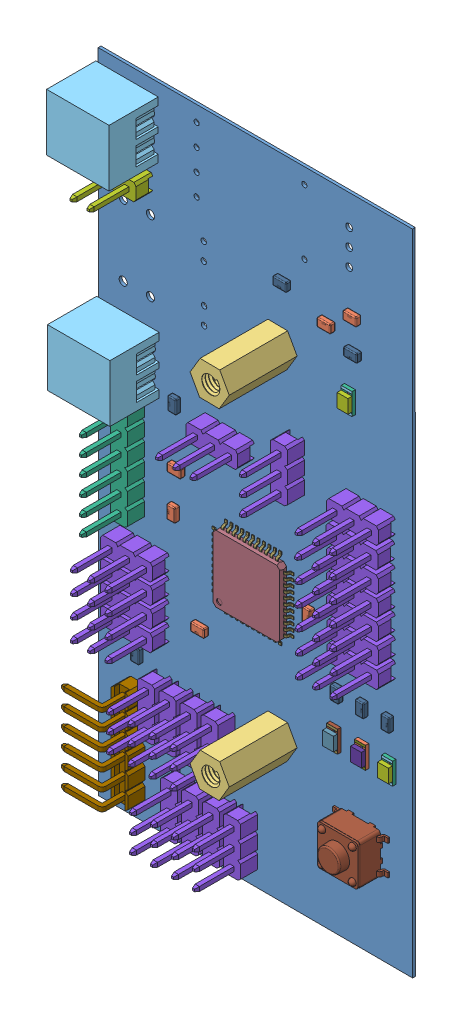
SolidWorks assembly PCBdroneV21, configuration Défaut. Lengths in mm.
Overall size (46.68 95.58 18.25).
198 component instances, 31 part files, 0 mates.
Components (placement in the parent):
- Board-1: Board [Défaut] at (0 0 -0.4115) size (46.33 95.58 0.41)
- C7-1: C7 [Défaut] at origin size (2 1.25 0.78)
  - C0805C-1: C0805C [Défaut] at (32.5373 81.5192 0) x (1 0 0) z (0 -1 0) size (2 0.78 1.25)
- C9-1: C9 [Défaut] at origin size (2 1.25 0.78)
  - C0805C-1: C0805C [Défaut] at (36.3473 84.3132 0) x (1 0 0) z (0 -1 0) size (2 0.78 1.25)
- Cdecoup1-1: Cdecoup1 [Défaut] at origin size (2 1.25 0.78)
  - C0805C-1: C0805C [Défaut] at (13.8939 33.335 0) x (-1 0 0) z (0 1 0) size (2 0.78 1.25)
- Cdecoup2-1: Cdecoup2 [Défaut] at origin size (1.25 2 0.78)
  - C0805C-1: C0805C [Défaut] at (29.9364 43.1801 0) x (0 -1 0) z (-1 0 0) size (2 0.78 1.25)
- Cdecoup4-1: Cdecoup4 [Défaut] at origin size (1.25 2 0.78)
  - C0805C-1: C0805C [Défaut] at (10.0178 46.2787 0) x (0 1 0) z (1 0 0) size (2 0.78 1.25)
- Cde-1: Cde [Défaut] at origin size (2 1.25 0.78)
  - C0805C-1: C0805C [Défaut] at (10.4393 51.9582 0) x (1 0 0) z (0 -1 0) size (2 0.78 1.25)
- D1-1: D1 [Défaut] at origin size (1.6 3.2 1.52)
  - SW3dPS-LED1206G-1: SW3dPS-LED1206G [Défaut] at (35.6997 71.852 0) x (0 1 0) z (0 0 1) size (3.2 1.6 1.52)
    - SW3dPS-LED1206G_Open_CASCADE_STEP_translator_6.2_262.2-1: SW3dPS-LED1206G_Open_CASCADE_STEP_translator_6.2_262.2 [Défaut] at origin size (3.2 1.6 1.1)
      - SW3dPS-LED1206G_352699472-1: SW3dPS-LED1206G_352699472 [Défaut] at (0.6096 0.0254 0.5027) size (0.65 0.76 0.01)
        - SW3dPS-LED1206G_Extruded-1: SW3dPS-LED1206G_Extruded [Défaut] at origin size (0.65 0.76 0.01)
      - SW3dPS-LED1206G_352698192-1: SW3dPS-LED1206G_352698192 [Défaut] at (2.1971 0.0254 0.5027) size (1.14 0.76 0.01)
        - SW3dPS-LED1206G_Extruded4-1: SW3dPS-LED1206G_Extruded4 [Défaut] at origin size (1.14 0.76 0.01)
      - SW3dPS-LED1206G_352697808-1: SW3dPS-LED1206G_352697808 [Défaut] at (0.1016 0.0127 0.5027) size (0.36 1.6 0.01)
        - SW3dPS-LED1206G_Extruded2-1: SW3dPS-LED1206G_Extruded2 [Défaut] at origin size (0.36 1.6 0.01)
      - SW3dPS-LED1206G_352697936-1: SW3dPS-LED1206G_352697936 [Défaut] at (1.524 0.0127 0.0127) size (3.2 1.6 0.49)
        - SW3dPS-LED1206G_Extruded1-1: SW3dPS-LED1206G_Extruded1 [Défaut] at origin size (3.2 1.6 0.49)
      - SW3dPS-LED1206G_352697808-2: SW3dPS-LED1206G_352697808 [Défaut] at (2.9464 0.0127 0.5027) size (0.36 1.6 0.01)
        - SW3dPS-LED1206G_Extruded2-1: SW3dPS-LED1206G_Extruded2 [Défaut] at origin size (0.36 1.6 0.01)
      - SW3dPS-LED1206G_352700880-1: SW3dPS-LED1206G_352700880 [Défaut] at (1.524 0.0127 0.5027) size (2.01 1.6 0.61)
        - SW3dPS-LED1206G_Extruded3-1: SW3dPS-LED1206G_Extruded3 [Défaut] at origin size (2.01 1.6 0.61)
    - SW3dPS-LED1206G_Board-1: SW3dPS-LED1206G_Board [Défaut] at (0 0 -0.4039) size (0.03 0.03 0.42)
- Ddebug1-1: Ddebug1 [Défaut] at origin size (1.6 3.2 1.52)
  - SW3dPS-LED1206R-1: SW3dPS-LED1206R [Défaut] at (33.5406 30.7341 0) x (0 -1 0) z (0 0 1) size (3.2 1.6 1.52)
    - SW3dPS-LED1206R_Board-1: SW3dPS-LED1206R_Board [Défaut] at (0 0 -0.4039) size (0.03 0.03 0.42)
    - SW3dPS-LED1206R_Open_CASCADE_STEP_translator_6.2_278.2-1: SW3dPS-LED1206R_Open_CASCADE_STEP_translator_6.2_278.2 [Défaut] at origin size (3.2 1.6 1.1)
      - SW3dPS-LED1206R_352699472-1: SW3dPS-LED1206R_352699472 [Défaut] at (0.6096 0.0254 0.5027) size (0.65 0.76 0.01)
        - SW3dPS-LED1206R_Extruded3-1: SW3dPS-LED1206R_Extruded3 [Défaut] at origin size (0.65 0.76 0.01)
      - SW3dPS-LED1206R_352697936-1: SW3dPS-LED1206R_352697936 [Défaut] at (1.524 0.0127 0.0127) size (3.2 1.6 0.49)
        - SW3dPS-LED1206R_Extruded1-1: SW3dPS-LED1206R_Extruded1 [Défaut] at origin size (3.2 1.6 0.49)
      - SW3dPS-LED1206R_352697808-1: SW3dPS-LED1206R_352697808 [Défaut] at (2.9464 0.0127 0.5027) size (0.36 1.6 0.01)
        - SW3dPS-LED1206R_Extruded-1: SW3dPS-LED1206R_Extruded [Défaut] at origin size (0.36 1.6 0.01)
      - SW3dPS-LED1206R_352698192-1: SW3dPS-LED1206R_352698192 [Défaut] at (2.1971 0.0254 0.5027) size (1.14 0.76 0.01)
        - SW3dPS-LED1206R_Extruded4-1: SW3dPS-LED1206R_Extruded4 [Défaut] at origin size (1.14 0.76 0.01)
      - SW3dPS-LED1206R_352697808-2: SW3dPS-LED1206R_352697808 [Défaut] at (0.1016 0.0127 0.5027) size (0.36 1.6 0.01)
        - SW3dPS-LED1206R_Extruded-1: SW3dPS-LED1206R_Extruded [Défaut] at origin size (0.36 1.6 0.01)
      - SW3dPS-LED1206R_352701008-1: SW3dPS-LED1206R_352701008 [Défaut] at (1.524 0.0127 0.5027) size (2.01 1.6 0.61)
        - SW3dPS-LED1206R_Extruded2-1: SW3dPS-LED1206R_Extruded2 [Défaut] at origin size (2.01 1.6 0.61)
- Ddebug2-1: Ddebug2 [Défaut] at origin size (1.6 3.2 1.52)
  - SW3dPS-LED1206Y-1: SW3dPS-LED1206Y [Défaut] at (37.6554 30.7341 0) x (0 -1 0) z (0 0 1) size (3.2 1.6 1.52)
    - SW3dPS-LED1206Y_Board-1: SW3dPS-LED1206Y_Board [Défaut] at (0 0 -0.4039) size (0.03 0.03 0.42)
    - SW3dPS-LED1206Y_Open_CASCADE_STEP_translator_6.2_294.2-1: SW3dPS-LED1206Y_Open_CASCADE_STEP_translator_6.2_294.2 [Défaut] at origin size (3.2 1.6 1.1)
      - SW3dPS-LED1206Y_352697808-1: SW3dPS-LED1206Y_352697808 [Défaut] at (0.1016 0.0127 0.5027) size (0.36 1.6 0.01)
        - SW3dPS-LED1206Y_Extruded2-1: SW3dPS-LED1206Y_Extruded2 [Défaut] at origin size (0.36 1.6 0.01)
      - SW3dPS-LED1206Y_352697680-1: SW3dPS-LED1206Y_352697680 [Défaut] at (1.524 0.0127 0.5027) size (2.01 1.6 0.61)
        - SW3dPS-LED1206Y_Extruded4-1: SW3dPS-LED1206Y_Extruded4 [Défaut] at origin size (2.01 1.6 0.61)
      - SW3dPS-LED1206Y_352698192-1: SW3dPS-LED1206Y_352698192 [Défaut] at (2.1971 0.0254 0.5027) size (1.14 0.76 0.01)
        - SW3dPS-LED1206Y_Extruded3-1: SW3dPS-LED1206Y_Extruded3 [Défaut] at origin size (1.14 0.76 0.01)
      - SW3dPS-LED1206Y_352699472-1: SW3dPS-LED1206Y_352699472 [Défaut] at (0.6096 0.0254 0.5027) size (0.65 0.76 0.01)
        - SW3dPS-LED1206Y_Extruded-1: SW3dPS-LED1206Y_Extruded [Défaut] at origin size (0.65 0.76 0.01)
      - SW3dPS-LED1206Y_352697936-1: SW3dPS-LED1206Y_352697936 [Défaut] at (1.524 0.0127 0.0127) size (3.2 1.6 0.49)
        - SW3dPS-LED1206Y_Extruded1-1: SW3dPS-LED1206Y_Extruded1 [Défaut] at origin size (3.2 1.6 0.49)
      - SW3dPS-LED1206Y_352697808-2: SW3dPS-LED1206Y_352697808 [Défaut] at (2.9464 0.0127 0.5027) size (0.36 1.6 0.01)
        - SW3dPS-LED1206Y_Extruded2-1: SW3dPS-LED1206Y_Extruded2 [Défaut] at origin size (0.36 1.6 0.01)
- Ddebug3-1: Ddebug3 [Défaut] at origin size (1.6 3.2 1.52)
  - SW3dPS-LED1206G-1: SW3dPS-LED1206G [Défaut] at (41.6433 30.7086 0) x (0 -1 0) z (0 0 1) size (3.2 1.6 1.52)
    - SW3dPS-LED1206G_Open_CASCADE_STEP_translator_6.2_262.2-1: SW3dPS-LED1206G_Open_CASCADE_STEP_translator_6.2_262.2 [Défaut] at origin size (3.2 1.6 1.1)
      - SW3dPS-LED1206G_352699472-1: SW3dPS-LED1206G_352699472 [Défaut] at (0.6096 0.0254 0.5027) size (0.65 0.76 0.01)
        - SW3dPS-LED1206G_Extruded-1: SW3dPS-LED1206G_Extruded [Défaut] at origin size (0.65 0.76 0.01)
      - SW3dPS-LED1206G_352698192-1: SW3dPS-LED1206G_352698192 [Défaut] at (2.1971 0.0254 0.5027) size (1.14 0.76 0.01)
        - SW3dPS-LED1206G_Extruded4-1: SW3dPS-LED1206G_Extruded4 [Défaut] at origin size (1.14 0.76 0.01)
      - SW3dPS-LED1206G_352697808-1: SW3dPS-LED1206G_352697808 [Défaut] at (0.1016 0.0127 0.5027) size (0.36 1.6 0.01)
        - SW3dPS-LED1206G_Extruded2-1: SW3dPS-LED1206G_Extruded2 [Défaut] at origin size (0.36 1.6 0.01)
      - SW3dPS-LED1206G_352697936-1: SW3dPS-LED1206G_352697936 [Défaut] at (1.524 0.0127 0.0127) size (3.2 1.6 0.49)
        - SW3dPS-LED1206G_Extruded1-1: SW3dPS-LED1206G_Extruded1 [Défaut] at origin size (3.2 1.6 0.49)
      - SW3dPS-LED1206G_352697808-2: SW3dPS-LED1206G_352697808 [Défaut] at (2.9464 0.0127 0.5027) size (0.36 1.6 0.01)
        - SW3dPS-LED1206G_Extruded2-1: SW3dPS-LED1206G_Extruded2 [Défaut] at origin size (0.36 1.6 0.01)
      - SW3dPS-LED1206G_352700880-1: SW3dPS-LED1206G_352700880 [Défaut] at (1.524 0.0127 0.5027) size (2.01 1.6 0.61)
        - SW3dPS-LED1206G_Extruded3-1: SW3dPS-LED1206G_Extruded3 [Défaut] at origin size (2.01 1.6 0.61)
    - SW3dPS-LED1206G_Board-1: SW3dPS-LED1206G_Board [Défaut] at (0 0 -0.4039) size (0.03 0.03 0.42)
- HOLE1-1: HOLE1 [Défaut] at origin size (5.77 5.05 18.25)
  - User_Library-Spacer-M3-10mm-1: User_Library-Spacer-M3-10mm [Défaut] at (25.0001 75.0001 0) x (1 0 0) z (0 -1 0) size (5.77 18.25 5.05)
  - User_Library-Female_screw_M3-1: User_Library-Female_screw_M3 [Défaut] at (25.0001 75.0001 -3.8) x (1 0 0) z (0 -1 0) size (5.77 3 5.05)
- HOLE2-1: HOLE2 [Défaut] at origin size (5.77 5.05 18.25)
  - User_Library-Spacer-M3-10mm-1: User_Library-Spacer-M3-10mm [Défaut] at (25.0001 25.0001 0) x (1 0 0) z (0 -1 0) size (5.77 18.25 5.05)
  - User_Library-Female_screw_M3-1: User_Library-Female_screw_M3 [Défaut] at (25.0001 25.0001 -3.8) x (1 0 0) z (0 -1 0) size (5.77 3 5.05)
- PBat-1: PBat [Défaut] at origin size (9.2 8.4 10.65)
  - User_Library-CTB93HD_2-1: User_Library-CTB93HD_2 [Défaut] at (6.2231 95.347 0) x (0 0 -1) z (0 1 0) size (10.65 9.2 8.4)
- Paccelgyro-1: Paccelgyro [Défaut] at origin size (2.5 15.24 11.2)
  - pin_header_aw140-eg-g06d-1: pin_header_aw140-eg-g06d [Défaut] at (4.1657 50.6475 0) x (0 -1 0) z (1 0 0) size (15.24 11.2 2.5)
- Palarm-1: Palarm [Défaut] at origin size (5.08 2.5 11.2)
  - pin_header_aw140-eg-g02d-1: pin_header_aw140-eg-g02d [Défaut] at (4.0387 86.3855 0) x (1 0 0) z (0 1 0) size (5.08 11.2 2.5)
- PAN0-1: PAN0 [Défaut] at origin size (2.5 7.62 11.2)
  - pin_header_aw140-eg-g03d-1: pin_header_aw140-eg-g03d [Défaut] at (8.1789 21.0819 0) x (0 -1 0) z (1 0 0) size (7.62 11.2 2.5)
- PAN1-1: PAN1 [Défaut] at origin size (2.5 7.62 11.2)
  - pin_header_aw140-eg-g03d-1: pin_header_aw140-eg-g03d [Défaut] at (11.3031 21.0819 0) x (0 -1 0) z (1 0 0) size (7.62 11.2 2.5)
- PAN6-1: PAN6 [Défaut] at origin size (2.5 7.62 11.2)
  - pin_header_aw140-eg-g03d-1: pin_header_aw140-eg-g03d [Défaut] at (14.4019 21.0819 0) x (0 -1 0) z (1 0 0) size (7.62 11.2 2.5)
- PAN7-1: PAN7 [Défaut] at origin size (2.5 7.62 11.2)
  - pin_header_aw140-eg-g03d-1: pin_header_aw140-eg-g03d [Défaut] at (17.5007 21.1073 0) x (0 -1 0) z (1 0 0) size (7.62 11.2 2.5)
- Pext-1: Pext [Défaut] at origin size (9.2 8.4 10.65)
  - User_Library-CTB93HD_2-1: User_Library-CTB93HD_2 [Défaut] at (6.3501 65.375 0) x (0 0 -1) z (0 1 0) size (10.65 9.2 8.4)
- Pickit-1: Pickit [Défaut] at origin size (7.1 15.04 11.14)
  - pin_header_aw140-ea-g06h-1: pin_header_aw140-ea-g06h [Défaut] at (4.2419 14.3255 2.5) x (0 1 0) z (1 0 0) size (15.04 11.14 7.1)
- Pjump0-1: Pjump0 [Défaut] at origin size (2.5 7.62 11.2)
  - pin_header_aw140-eg-g03d-1: pin_header_aw140-eg-g03d [Défaut] at (11.5569 9.9315 0) x (0 1 0) z (-1 0 0) size (7.62 11.2 2.5)
- Pjump1-1: Pjump1 [Défaut] at origin size (2.5 7.62 11.2)
  - pin_header_aw140-eg-g03d-1: pin_header_aw140-eg-g03d [Défaut] at (14.6473 9.9315 0) x (0 1 0) z (-1 0 0) size (7.62 11.2 2.5)
- Pjump6-1: Pjump6 [Défaut] at origin size (2.5 7.62 11.2)
  - pin_header_aw140-eg-g03d-1: pin_header_aw140-eg-g03d [Défaut] at (17.7376 9.9315 0) x (0 1 0) z (-1 0 0) size (7.62 11.2 2.5)
- Pjump7-1: Pjump7 [Défaut] at origin size (2.5 7.62 11.2)
  - pin_header_aw140-eg-g03d-1: pin_header_aw140-eg-g03d [Défaut] at (20.8279 9.9315 0) x (0 1 0) z (-1 0 0) size (7.62 11.2 2.5)
- Prec-1: Prec [Défaut] at origin size (7.62 2.5 11.2)
  - pin_header_aw140-eg-g03d-1: pin_header_aw140-eg-g03d [Défaut] at (38.5065 60.4013 0) x (1 0 0) z (0 1 0) size (7.62 11.2 2.5)
- Prec2-1: Prec2 [Défaut] at origin size (7.62 2.5 11.2)
  - pin_header_aw140-eg-g03d-1: pin_header_aw140-eg-g03d [Défaut] at (38.4811 51.1303 0) x (1 0 0) z (0 1 0) size (7.62 11.2 2.5)
- Prec3-1: Prec3 [Défaut] at origin size (7.62 2.5 11.2)
  - pin_header_aw140-eg-g03d-1: pin_header_aw140-eg-g03d [Défaut] at (38.4811 54.1529 0) x (1 0 0) z (0 1 0) size (7.62 11.2 2.5)
- Prec4-1: Prec4 [Défaut] at origin size (7.62 2.5 11.2)
  - pin_header_aw140-eg-g03d-1: pin_header_aw140-eg-g03d [Défaut] at (38.4303 57.2263 0) x (1 0 0) z (0 1 0) size (7.62 11.2 2.5)
- Prec5-1: Prec5 [Défaut] at origin size (7.62 2.5 11.2)
  - pin_header_aw140-eg-g03d-1: pin_header_aw140-eg-g03d [Défaut] at (38.5319 42.0117 0) x (1 0 0) z (0 1 0) size (7.62 11.2 2.5)
- Prec6-1: Prec6 [Défaut] at origin size (7.62 2.5 11.2)
  - pin_header_aw140-eg-g03d-1: pin_header_aw140-eg-g03d [Défaut] at (38.5319 45.0597 0) x (1 0 0) z (0 1 0) size (7.62 11.2 2.5)
- Prec7-1: Prec7 [Défaut] at origin size (7.62 2.5 11.2)
  - pin_header_aw140-eg-g03d-1: pin_header_aw140-eg-g03d [Défaut] at (38.5065 48.1331 0) x (1 0 0) z (0 1 0) size (7.62 11.2 2.5)
- Psend1-1: Psend1 [Défaut] at origin size (7.62 2.5 11.2)
  - pin_header_aw140-eg-g03d-1: pin_header_aw140-eg-g03d [Défaut] at (5.3847 39.0651 0) x (-1 0 0) z (0 -1 0) size (7.62 11.2 2.5)
- Psend2-1: Psend2 [Défaut] at origin size (7.62 2.5 11.2)
  - pin_header_aw140-eg-g03d-1: pin_header_aw140-eg-g03d [Défaut] at (5.3847 36.0595 0) x (-1 0 0) z (0 -1 0) size (7.62 11.2 2.5)
- Psend3-1: Psend3 [Défaut] at origin size (7.62 2.5 11.2)
  - pin_header_aw140-eg-g03d-1: pin_header_aw140-eg-g03d [Défaut] at (5.3847 33.0538 0) x (-1 0 0) z (0 -1 0) size (7.62 11.2 2.5)
- Psend4-1: Psend4 [Défaut] at origin size (7.62 2.5 11.2)
  - pin_header_aw140-eg-g03d-1: pin_header_aw140-eg-g03d [Défaut] at (5.3847 30.0481 0) x (-1 0 0) z (0 -1 0) size (7.62 11.2 2.5)
- Pservo-1: Pservo [Défaut] at origin size (2.5 7.62 11.2)
  - pin_header_aw140-eg-g03d-1: pin_header_aw140-eg-g03d [Défaut] at (27.7367 61.1633 0) x (0 1 0) z (-1 0 0) size (7.62 11.2 2.5)
- Puart-1: Puart [Défaut] at origin size (7.62 2.5 11.2)
  - pin_header_aw140-eg-g03d-1: pin_header_aw140-eg-g03d [Défaut] at (17.9323 59.7153 0) x (-1 0 0) z (0 -1 0) size (7.62 11.2 2.5)
- R1-1: R1 [Défaut] at origin size (2 1.25 0.78)
  - SW3dPS-0805_SMD_Resistor-1: SW3dPS-0805_SMD_Resistor [Défaut] at (36.449 79.7259 0) x (-1 0 0) z (0 1 0) size (2 0.78 1.25)
- Rd1-1: Rd1 [Défaut] at origin size (1.25 2 0.78)
  - SW3dPS-0805_SMD_Resistor-1: SW3dPS-0805_SMD_Resistor [Défaut] at (34.0869 35.2298 0) x (0 -1 0) z (-1 0 0) size (2 0.78 1.25)
- Rd2-1: Rd2 [Défaut] at origin size (1.25 2 0.78)
  - SW3dPS-0805_SMD_Resistor-1: SW3dPS-0805_SMD_Resistor [Défaut] at (37.7953 35.2044 0) x (0 -1 0) z (-1 0 0) size (2 0.78 1.25)
- Rd3-1: Rd3 [Défaut] at origin size (1.25 2 0.78)
  - SW3dPS-0805_SMD_Resistor-1: SW3dPS-0805_SMD_Resistor [Défaut] at (41.5799 35.2298 0) x (0 -1 0) z (-1 0 0) size (2 0.78 1.25)
- reset-1: reset [Défaut] at origin size (8.15 6 5.05)
  - CircuitWorks-TACT_SMD_6X6-1: CircuitWorks-TACT_SMD_6X6 [Défaut] at (37.4613 17.8159 0) x (1 0 0) z (0 -1 0) size (8.15 5.05 6)
- Rp1-1: Rp1 [Défaut] at origin size (1.25 2 0.78)
  - SW3dPS-0805_SMD_Resistor-1: SW3dPS-0805_SMD_Resistor [Défaut] at (4.6735 25.527 0) x (0 1 0) z (1 0 0) size (2 0.78 1.25)
- Rpup-1: Rpup [Défaut] at origin size (1.25 2 0.78)
  - SW3dPS-0805_SMD_Resistor-1: SW3dPS-0805_SMD_Resistor [Défaut] at (10.1599 60.168 0) x (0 1 0) z (1 0 0) size (2 0.78 1.25)
- Rset-1: Rset [Défaut] at origin size (2 1.25 0.78)
  - SW3dPS-0805_SMD_Resistor-1: SW3dPS-0805_SMD_Resistor [Défaut] at (26.035 83.5659 0) x (-1 0 0) z (0 1 0) size (2 0.78 1.25)
- U1-1: U1 [Défaut] at origin size (12 12 1.06)
  - User_Library-TQFP-44-1: User_Library-TQFP-44 [Défaut] at (21.4631 42.8961 0.55) size (12 12 1.06)
    - User_Library-TQFP-44_pins_TQFP_pin_TQFP_035_1-1: User_Library-TQFP-44_pins_TQFP_pin_TQFP_035_1 [Défaut] at (6 2.225 -0.5) x (0 1 0) z (1 0 0) size (0.35 0.62 1)
    - User_Library-TQFP-44_pins_TQFP_pin_TQFP_035_1-2: User_Library-TQFP-44_pins_TQFP_pin_TQFP_035_1 [Défaut] at (-6 -2.225 -0.5) x (0 -1 0) z (-1 0 0) size (0.35 0.62 1)
    - User_Library-TQFP-44_pins_TQFP_pin_TQFP_035_1-3: User_Library-TQFP-44_pins_TQFP_pin_TQFP_035_1 [Défaut] at (-6 3.375 -0.5) x (0 -1 0) z (-1 0 0) size (0.35 0.62 1)
    - User_Library-TQFP-44_pins_TQFP_pin_TQFP_035_1-4: User_Library-TQFP-44_pins_TQFP_pin_TQFP_035_1 [Défaut] at (6 -0.975 -0.5) x (0 1 0) z (1 0 0) size (0.35 0.62 1)
    - User_Library-TQFP-44_pins_TQFP_pin_TQFP_035_1-5: User_Library-TQFP-44_pins_TQFP_pin_TQFP_035_1 [Défaut] at (3.375 6 -0.5) x (-1 0 0) z (0 1 0) size (0.35 0.62 1)
    - User_Library-TQFP-44_pins_TQFP_pin_TQFP_035_1-6: User_Library-TQFP-44_pins_TQFP_pin_TQFP_035_1 [Défaut] at (-6 0.975 -0.5) x (0 -1 0) z (-1 0 0) size (0.35 0.62 1)
    - User_Library-TQFP-44_pins_TQFP_pin_TQFP_035_1-7: User_Library-TQFP-44_pins_TQFP_pin_TQFP_035_1 [Défaut] at (0.625 -6 -0.5) x (1 0 0) z (0 -1 0) size (0.35 0.62 1)
    - User_Library-TQFP-44_pins_TQFP_pin_TQFP_035_1-8: User_Library-TQFP-44_pins_TQFP_pin_TQFP_035_1 [Défaut] at (0.175 6 -0.5) x (-1 0 0) z (0 1 0) size (0.35 0.62 1)
    - User_Library-TQFP-44_pins_TQFP_pin_TQFP_035_1-9: User_Library-TQFP-44_pins_TQFP_pin_TQFP_035_1 [Défaut] at (-2.575 -6 -0.5) x (1 0 0) z (0 -1 0) size (0.35 0.62 1)
    - User_Library-TQFP-44_pins_TQFP_pin_TQFP_035_1-10: User_Library-TQFP-44_pins_TQFP_pin_TQFP_035_1 [Défaut] at (-3.375 -6 -0.5) x (1 0 0) z (0 -1 0) size (0.35 0.62 1)
    - User_Library-TQFP-44_pins_TQFP_pin_TQFP_035_1-11: User_Library-TQFP-44_pins_TQFP_pin_TQFP_035_1 [Défaut] at (6 1.425 -0.5) x (0 1 0) z (1 0 0) size (0.35 0.62 1)
    - User_Library-TQFP-44_pins_TQFP_pin_TQFP_035_1-12: User_Library-TQFP-44_pins_TQFP_pin_TQFP_035_1 [Défaut] at (-6 -3.025 -0.5) x (0 -1 0) z (-1 0 0) size (0.35 0.62 1)
    - User_Library-TQFP-44_pins_TQFP_pin_TQFP_035_1-13: User_Library-TQFP-44_pins_TQFP_pin_TQFP_035_1 [Défaut] at (2.575 6 -0.5) x (-1 0 0) z (0 1 0) size (0.35 0.62 1)
    - User_Library-TQFP-44_pins_TQFP_pin_TQFP_035_1-14: User_Library-TQFP-44_pins_TQFP_pin_TQFP_035_1 [Défaut] at (1.775 6 -0.5) x (-1 0 0) z (0 1 0) size (0.35 0.62 1)
    - User_Library-TQFP-44_pins_TQFP_pin_TQFP_035_1-15: User_Library-TQFP-44_pins_TQFP_pin_TQFP_035_1 [Défaut] at (-0.975 -6 -0.5) x (1 0 0) z (0 -1 0) size (0.35 0.62 1)
    - User_Library-TQFP-44_pins_TQFP_pin_TQFP_035_1-16: User_Library-TQFP-44_pins_TQFP_pin_TQFP_035_1 [Défaut] at (-0.175 -6 -0.5) x (1 0 0) z (0 -1 0) size (0.35 0.62 1)
    - User_Library-TQFP-44_pins_TQFP_pin_TQFP_035_1-17: User_Library-TQFP-44_pins_TQFP_pin_TQFP_035_1 [Défaut] at (-0.625 6 -0.5) x (-1 0 0) z (0 1 0) size (0.35 0.62 1)
    - User_Library-TQFP-44_pins_TQFP_pin_TQFP_035_1-18: User_Library-TQFP-44_pins_TQFP_pin_TQFP_035_1 [Défaut] at (-3.025 6 -0.5) x (-1 0 0) z (0 1 0) size (0.35 0.62 1)
    - User_Library-TQFP-44_pins_TQFP_pin_TQFP_035_1-19: User_Library-TQFP-44_pins_TQFP_pin_TQFP_035_1 [Défaut] at (6 -4.175 -0.5) x (0 1 0) z (1 0 0) size (0.35 0.62 1)
    - User_Library-TQFP-44_pins_TQFP_pin_TQFP_035_1-20: User_Library-TQFP-44_pins_TQFP_pin_TQFP_035_1 [Défaut] at (6 3.025 -0.5) x (0 1 0) z (1 0 0) size (0.35 0.62 1)
    - User_Library-TQFP-44_pins_TQFP_pin_TQFP_035_1-21: User_Library-TQFP-44_pins_TQFP_pin_TQFP_035_1 [Défaut] at (2.225 -6 -0.5) x (1 0 0) z (0 -1 0) size (0.35 0.62 1)
    - User_Library-TQFP-44_pins_TQFP_pin_TQFP_035_1-22: User_Library-TQFP-44_pins_TQFP_pin_TQFP_035_1 [Défaut] at (-6 -1.425 -0.5) x (0 -1 0) z (-1 0 0) size (0.35 0.62 1)
    - User_Library-TQFP-44_pins_TQFP_pin_TQFP_035_1-23: User_Library-TQFP-44_pins_TQFP_pin_TQFP_035_1 [Défaut] at (-6 4.175 -0.5) x (0 -1 0) z (-1 0 0) size (0.35 0.62 1)
    - User_Library-TQFP-44_pins_TQFP_pin_TQFP_035_1-24: User_Library-TQFP-44_pins_TQFP_pin_TQFP_035_1 [Défaut] at (6 -0.175 -0.5) x (0 1 0) z (1 0 0) size (0.35 0.62 1)
    - User_Library-TQFP-44_pins_TQFP_pin_TQFP_035_1-25: User_Library-TQFP-44_pins_TQFP_pin_TQFP_035_1 [Défaut] at (4.175 6 -0.5) x (-1 0 0) z (0 1 0) size (0.35 0.62 1)
    - User_Library-TQFP-44_pins_TQFP_pin_TQFP_035_1-26: User_Library-TQFP-44_pins_TQFP_pin_TQFP_035_1 [Défaut] at (-6 1.775 -0.5) x (0 -1 0) z (-1 0 0) size (0.35 0.62 1)
    - User_Library-TQFP-44_pins_TQFP_pin_TQFP_035_1-27: User_Library-TQFP-44_pins_TQFP_pin_TQFP_035_1 [Défaut] at (-6 0.175 -0.5) x (0 -1 0) z (-1 0 0) size (0.35 0.62 1)
    - User_Library-TQFP-44_pins_TQFP_pin_TQFP_035_1-28: User_Library-TQFP-44_pins_TQFP_pin_TQFP_035_1 [Défaut] at (6 -1.775 -0.5) x (0 1 0) z (1 0 0) size (0.35 0.62 1)
    - User_Library-TQFP-44_pins_TQFP_pin_TQFP_035_1-29: User_Library-TQFP-44_pins_TQFP_pin_TQFP_035_1 [Défaut] at (-3.825 6 -0.5) x (-1 0 0) z (0 1 0) size (0.35 0.62 1)
    - User_Library-TQFP-44_pins_TQFP_pin_TQFP_035_1-30: User_Library-TQFP-44_pins_TQFP_pin_TQFP_035_1 [Défaut] at (6 0.625 -0.5) x (0 1 0) z (1 0 0) size (0.35 0.62 1)
    - User_Library-TQFP-44_pins_TQFP_pin_TQFP_035_1-31: User_Library-TQFP-44_pins_TQFP_pin_TQFP_035_1 [Défaut] at (-6 -3.825 -0.5) x (0 -1 0) z (-1 0 0) size (0.35 0.62 1)
    - User_Library-TQFP-44_pins_TQFP_pin_TQFP_035_1-32: User_Library-TQFP-44_pins_TQFP_pin_TQFP_035_1 [Défaut] at (-6 2.575 -0.5) x (0 -1 0) z (-1 0 0) size (0.35 0.62 1)
    - User_Library-TQFP-44_pins_TQFP_pin_TQFP_035_1-33: User_Library-TQFP-44_pins_TQFP_pin_TQFP_035_1 [Défaut] at (-1.425 6 -0.5) x (-1 0 0) z (0 1 0) size (0.35 0.62 1)
    - User_Library-TQFP-44_pins_TQFP_pin_TQFP_035_1-34: User_Library-TQFP-44_pins_TQFP_pin_TQFP_035_1 [Défaut] at (6 -2.575 -0.5) x (0 1 0) z (1 0 0) size (0.35 0.62 1)
    - User_Library-TQFP-44_pins_TQFP_pin_TQFP_035_1-35: User_Library-TQFP-44_pins_TQFP_pin_TQFP_035_1 [Défaut] at (-4.175 -6 -0.5) x (1 0 0) z (0 -1 0) size (0.35 0.62 1)
    - User_Library-TQFP-44_pins_TQFP_pin_TQFP_035_1-36: User_Library-TQFP-44_pins_TQFP_pin_TQFP_035_1 [Défaut] at (3.825 -6 -0.5) x (1 0 0) z (0 -1 0) size (0.35 0.62 1)
    - User_Library-TQFP-44_pins_TQFP_pin_TQFP_035_1-37: User_Library-TQFP-44_pins_TQFP_pin_TQFP_035_1 [Défaut] at (1.425 -6 -0.5) x (1 0 0) z (0 -1 0) size (0.35 0.62 1)
    - User_Library-TQFP-44_pins_TQFP_pin_TQFP_035_1-38: User_Library-TQFP-44_pins_TQFP_pin_TQFP_035_1 [Défaut] at (0.975 6 -0.5) x (-1 0 0) z (0 1 0) size (0.35 0.62 1)
    - User_Library-TQFP-44_pins_TQFP_pin_TQFP_035_1-39: User_Library-TQFP-44_pins_TQFP_pin_TQFP_035_1 [Défaut] at (-1.775 -6 -0.5) x (1 0 0) z (0 -1 0) size (0.35 0.62 1)
    - User_Library-TQFP-44_pins_TQFP_pin_TQFP_035_1-40: User_Library-TQFP-44_pins_TQFP_pin_TQFP_035_1 [Défaut] at (-2.225 6 -0.5) x (-1 0 0) z (0 1 0) size (0.35 0.62 1)
    - User_Library-TQFP-44_pins_TQFP_pin_TQFP_035_1-41: User_Library-TQFP-44_pins_TQFP_pin_TQFP_035_1 [Défaut] at (6 -3.375 -0.5) x (0 1 0) z (1 0 0) size (0.35 0.62 1)
    - User_Library-TQFP-44_pins_TQFP_pin_TQFP_035_1-42: User_Library-TQFP-44_pins_TQFP_pin_TQFP_035_1 [Défaut] at (6 3.825 -0.5) x (0 1 0) z (1 0 0) size (0.35 0.62 1)
    - User_Library-TQFP-44_pins_TQFP_pin_TQFP_035_1-43: User_Library-TQFP-44_pins_TQFP_pin_TQFP_035_1 [Défaut] at (3.025 -6 -0.5) x (1 0 0) z (0 -1 0) size (0.35 0.62 1)
    - User_Library-TQFP-44_pins_TQFP_pin_TQFP_035_1-44: User_Library-TQFP-44_pins_TQFP_pin_TQFP_035_1 [Défaut] at (-6 -0.625 -0.5) x (0 -1 0) z (-1 0 0) size (0.35 0.62 1)
    - User_Library-TQFP-44_body_10x1_TQFP_10x10_1-1: User_Library-TQFP-44_body_10x1_TQFP_10x10_1 [Défaut] at (0 0 -0.5) size (10 10 1)
